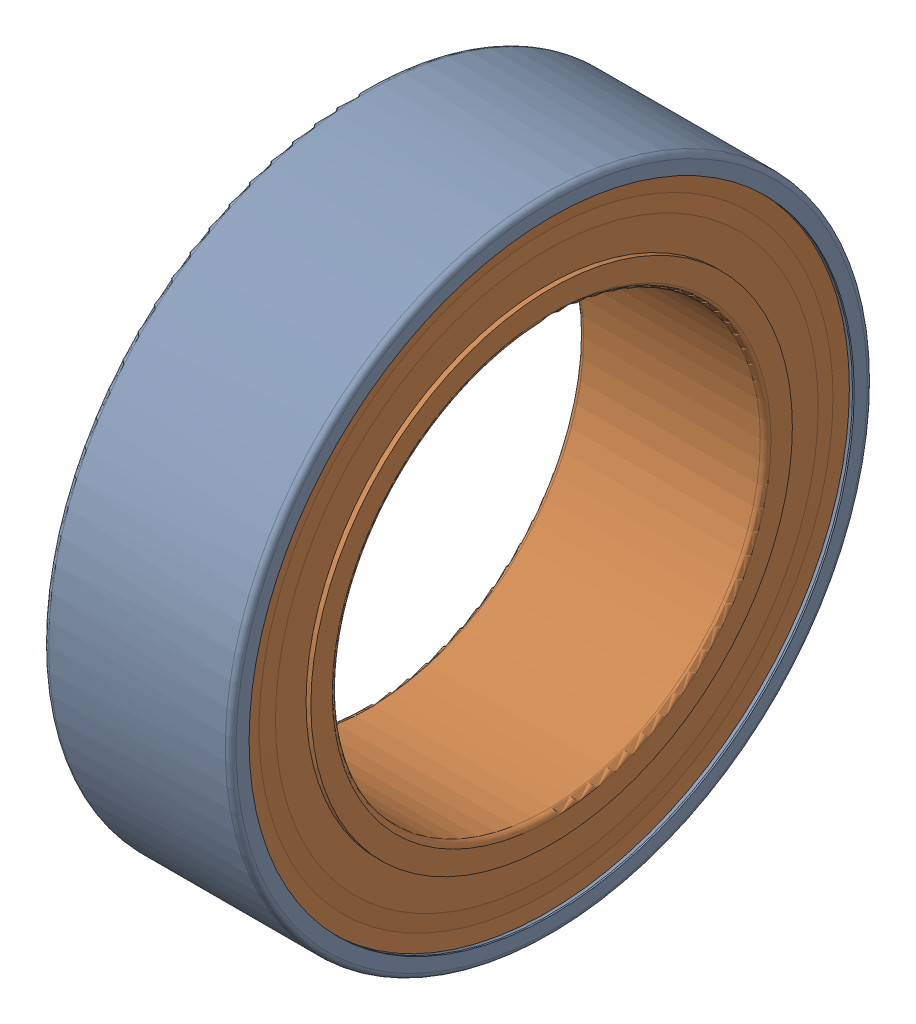
SolidWorks assembly SKF_W 637_8-2Z, configuration Default. Lengths in mm.
Overall size (3.5 12 12).
14 component instances, 3 part files, 0 mates.
Components (placement in the parent):
- SKF_W 637_8-2Z_ball1-1: SKF_W 637_8-2Z_ball1 [Default] at (3.5 9.2368 -2.475) x (-1 0 0) z (0 0 1) size (1.2 1.2 1.2)
- SKF_W 637_8-2Z_ball1-2: SKF_W 637_8-2Z_ball1 [Default] at (3.5 7.425 -4.2868) x (-1 0 0) z (0 0 1) size (1.2 1.2 1.2)
- SKF_W 637_8-2Z_ball1-3: SKF_W 637_8-2Z_ball1 [Default] at (3.5 4.95 -4.95) x (-1 0 0) z (0 0 1) size (1.2 1.2 1.2)
- SKF_W 637_8-2Z_ball1-4: SKF_W 637_8-2Z_ball1 [Default] at (3.5 2.475 -4.2868) x (-1 0 0) z (0 0 1) size (1.2 1.2 1.2)
- SKF_W 637_8-2Z_ball1-5: SKF_W 637_8-2Z_ball1 [Default] at (3.5 0.6632 -2.475) x (-1 0 0) z (0 0 1) size (1.2 1.2 1.2)
- SKF_W 637_8-2Z_ball1-6: SKF_W 637_8-2Z_ball1 [Default] at (3.5 0 0) x (-1 0 0) z (0 0 1) size (1.2 1.2 1.2)
- SKF_W 637_8-2Z_ball1-7: SKF_W 637_8-2Z_ball1 [Default] at (3.5 0.6632 2.475) x (-1 0 0) z (0 0 1) size (1.2 1.2 1.2)
- SKF_W 637_8-2Z_ball1-8: SKF_W 637_8-2Z_ball1 [Default] at (3.5 2.475 4.2868) x (-1 0 0) z (0 0 1) size (1.2 1.2 1.2)
- SKF_W 637_8-2Z_ball1-9: SKF_W 637_8-2Z_ball1 [Default] at (3.5 4.95 4.95) x (-1 0 0) z (0 0 1) size (1.2 1.2 1.2)
- SKF_W 637_8-2Z_ball1-10: SKF_W 637_8-2Z_ball1 [Default] at (3.5 7.425 4.2868) x (-1 0 0) z (0 0 1) size (1.2 1.2 1.2)
- SKF_W 637_8-2Z_ball1-11: SKF_W 637_8-2Z_ball1 [Default] at (3.5 9.2368 2.475) x (-1 0 0) z (0 0 1) size (1.2 1.2 1.2)
- SKF_W 637_8-2Z_ball1-12: SKF_W 637_8-2Z_ball1 [Default] at (3.5 9.9 0) x (-1 0 0) z (0 0 1) size (1.2 1.2 1.2)
- SKF_W 637_8-2Z_or-1: SKF_W 637_8-2Z_or [Default] x (1 0 0) z (0 0 -1) size (3.5 12 12)
- SKF_W 637_8-2Z_ir-1: SKF_W 637_8-2Z_ir [Default] x (1 0 0) z (0 0 -1) size (3.5 11.31 11.31)
